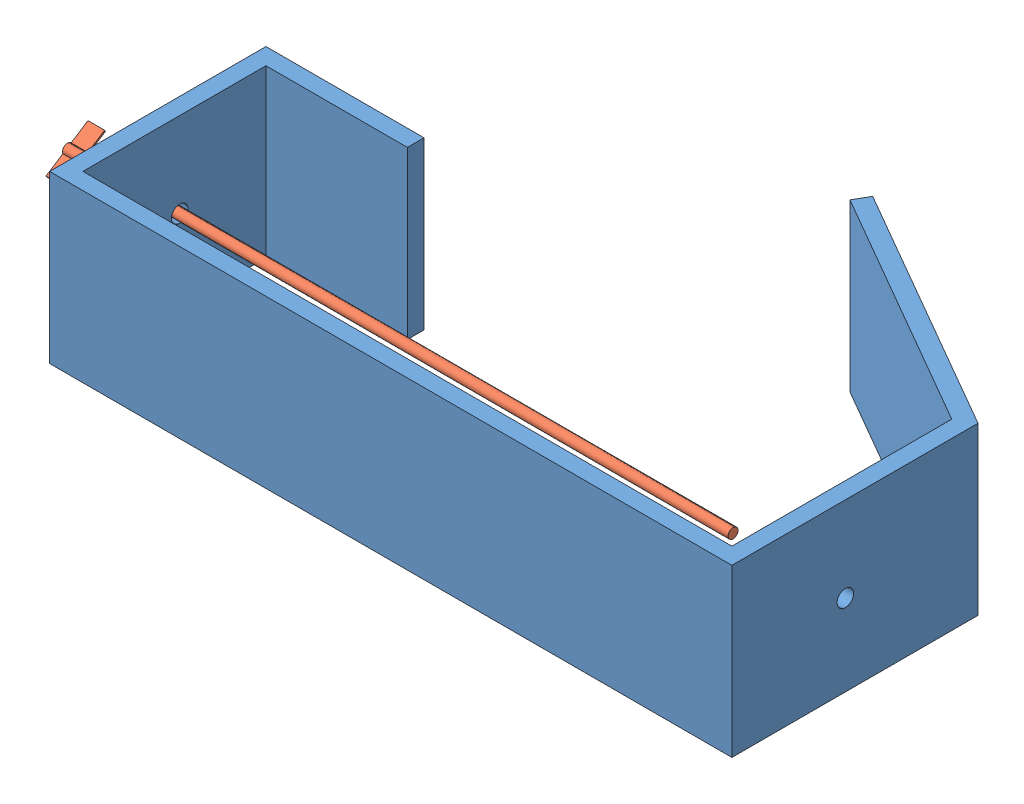
SolidWorks assembly Assem1, configuration Default. Lengths in mm.
Overall size (233.74 50 117.17).
2 component instances, 2 part files, 1 mates.
Components (placement in the parent):
- Piece midterm-1: Piece midterm [Default] at (118.4346 100.6886 139.5122) size (205 50 117.17)
- tube midterm-1: tube midterm [Default] at (60.8102 125.1403 220.4219) x (0 0.541269 -0.84085) z (0 0.84085 0.541269) size (15 200 3)
Mates (geometry in assembly coordinates):
- Concentric3: concentric aligned: cylinder of Piece midterm-1 through (-10.4532 125.1403 220.4219) axis (1 0 0) radius 2.5; cylinder of tube midterm-1 through (144.1195 125.1403 220.4219) axis (1 0 0) radius 1.5
